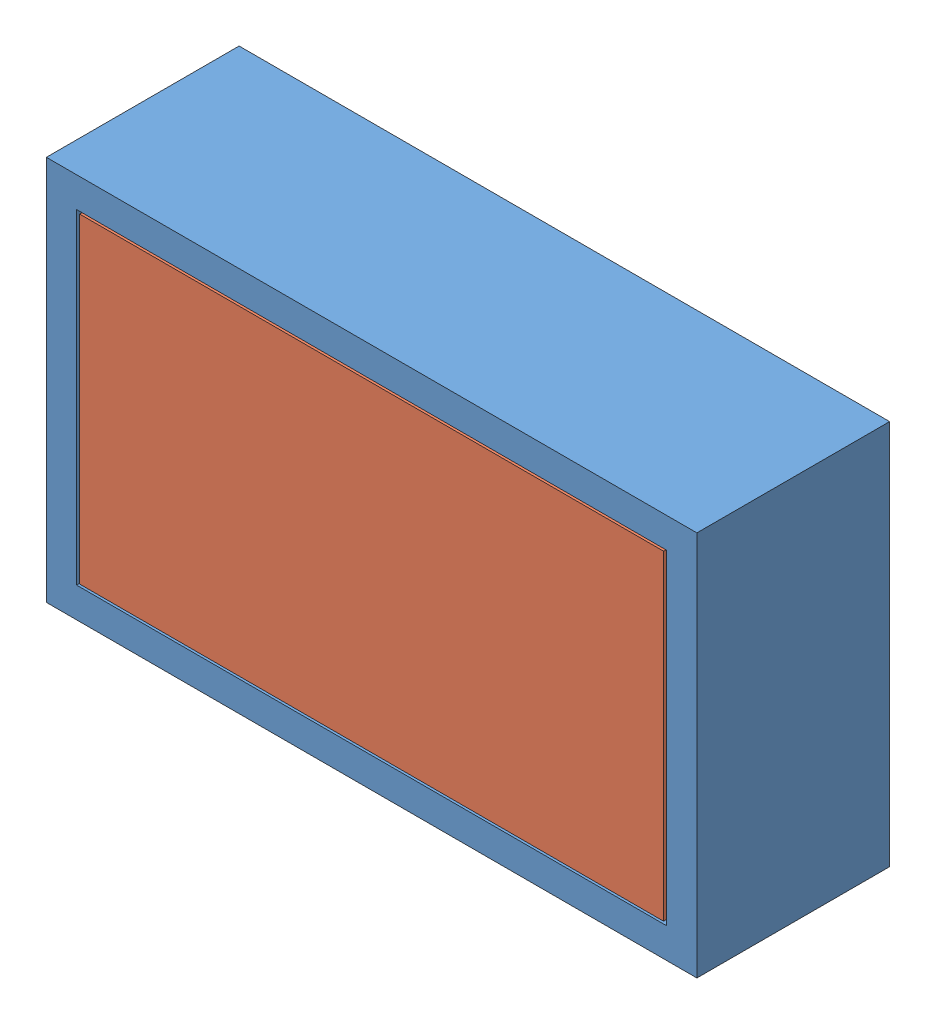
SolidWorks assembly Assembly, configuration Default. Lengths in mm.
Overall size (135 80 40).
2 component instances, 2 part files, 3 mates.
Components (placement in the parent):
- Mold-1: Mold [Default] at (-28.5341 55.7531 98.1949) size (135 80 40)
- 125B_4P_1S-2: 125B_4P_1S [Default] at (38.9659 95.7531 98.1949) size (121.2 66.5 35)
Mates (geometry in assembly coordinates):
- Coincident1: coincident: plane of Mold-1 through (38.9659 55.7531 98.1949) normal (1 0 0); plane of 125B_4P_1S-2 through (38.9659 95.7531 98.1949) normal (1 0 0)
- Coincident4: coincident: plane of Mold-1 through (-28.5341 55.7531 98.1949) normal (0 0 1); plane of 125B_4P_1S-2 through (38.9659 95.7531 98.1949) normal (0 0 1)
- Coincident5: coincident: plane of Mold-1 through (-28.5341 95.7531 98.1949) normal (0 1 0); plane of 125B_4P_1S-2 through (38.9659 95.7531 98.1949) normal (0 1 0)
